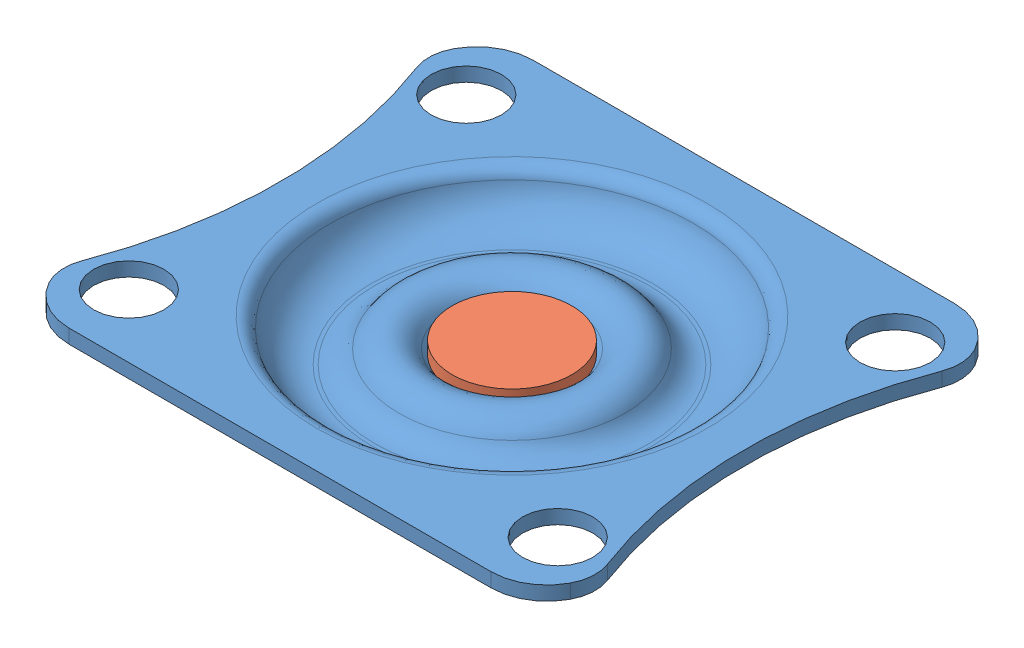
SolidWorks assembly A - Base, configuration Défaut. Lengths in mm.
Overall size (104.02 8 42.2).
3 component instances, 3 part files, 4 mates.
Components (placement in the parent):
- Base-1: Base [Défaut] at (-1.008 2.021 37.7647) size (104.02 4 42.2)
- Rivet A-1: Rivet A [Défaut] at (-1.008 -0.979 37.7647) size (8.5 5.5 8.5)
- Rivet B-1: Rivet B [Défaut] at (-1.008 -3.979 37.7647) size (10.5 5 10.5)
Mates (geometry in assembly coordinates):
- Coaxiale1: concentric aligned: cylinder of Base-1 through (-1.008 7.3947 37.7647) axis (0 1 0) radius 1.5; cylinder of Rivet A-1 through (-1.008 2.4333 37.7647) axis (0 1 0) radius 1.5
- Coïncidente1: coincident anti-aligned: plane of Base-1 through (-3.8298 -0.979 37.7647) normal (0 1 0); plane of Rivet A-1 through (-5.258 -0.979 37.7647) normal (0 -1 0)
- Coaxiale2: concentric aligned: cylinder of Rivet A-1 through (-1.008 2.4333 37.7647) axis (0 1 0) radius 1.5; cylinder of Rivet B-1 through (-1.008 23.2913 37.7647) axis (0 1 0) radius 1.5
- Distance1: distance = 2 mm anti-aligned: plane of Base-1 through (-3.8298 -1.979 37.7647) normal (0 -1 0); plane of Rivet B-1 through (-6.258 -3.979 37.7647) normal (0 1 0)
